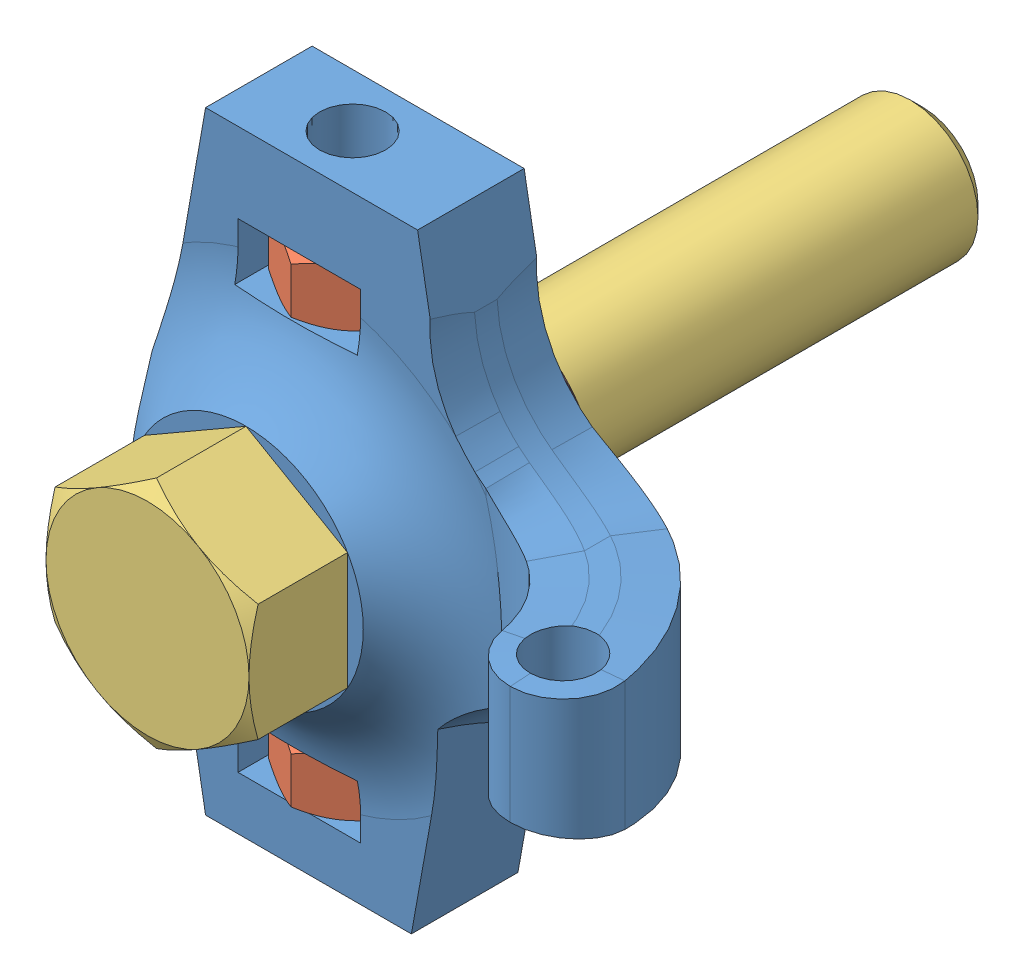
SolidWorks assembly newknuckle right, configuration Default. Lengths in mm.
Overall size (51.11 57.5 72.75).
5 component instances, 4 part files, 8 mates.
Components (placement in the parent):
- ANOTHERKNUCKLEHAHA-1: ANOTHERKNUCKLEHAHA [Default] at (-92.8759 12.7654 19.943) size (51.11 57.5 22.5)
- hex nut style 1_am-1: hex nut style 1_am [B18.2.4.1M - Hex nut, Style 1,  M6 x 1 --D-N] at (-92.8759 30.0654 24.943) x (1 0 0) z (0 -1 0) size (10 11.55 5.2)
- hex nut style 1_am-2: hex nut style 1_am [B18.2.4.1M - Hex nut, Style 1,  M6 x 1 --D-N] at (-92.8759 -9.7346 24.943) x (1 0 0) z (0 -1 0) size (10 11.55 5.2)
- hex bolt_ai-1: hex bolt_ai [HBOLT 0.5000-13x2.5x1.25-N] at (-92.8759 12.7654 44.1886) x (0 0 -1) z (1 0 0) size (72.75 22 19.05)
- hex jam nut_ai-1: hex jam nut_ai [HJNUT 0.5000-13-D-N] at (-92.8759 12.7654 11.7388) x (0.923728 0.383049 0) z (0 0 -1) size (19.05 22 8.2)
Mates (geometry in assembly coordinates):
- Concentric1: concentric anti-aligned: cylinder of ANOTHERKNUCKLEHAHA-1 through (-92.8759 -14.7346 24.943) axis (0 1 0) radius 3.1; cylinder of hex nut style 1_am-1 through (-92.8759 55.1029 24.943) axis (0 -1 0) radius 3
- Coincident1: coincident anti-aligned: plane of ANOTHERKNUCKLEHAHA-1 through (-92.8759 35.2654 29.943) normal (0 -1 0); plane of hex nut style 1_am-1 through (-102.8759 35.2654 24.943) normal (0 1 0)
- Concentric2: concentric anti-aligned: cylinder of ANOTHERKNUCKLEHAHA-1 through (-92.8759 -14.7346 24.943) axis (0 1 0) radius 3.1; cylinder of hex nut style 1_am-2 through (-92.8759 15.3029 24.943) axis (0 -1 0) radius 3
- Coincident2: coincident anti-aligned: plane of ANOTHERKNUCKLEHAHA-1 through (-92.8759 -4.5346 29.943) normal (0 -1 0); plane of hex nut style 1_am-2 through (-102.8759 -4.5346 24.943) normal (0 1 0)
- Concentric3: concentric anti-aligned: cylinder of ANOTHERKNUCKLEHAHA-1 through (-92.8759 12.7654 29.943) axis (0 0 -1) radius 6.4; cylinder of hex bolt_ai-1 through (-92.8759 12.7654 44.1886) axis (0 0 1) radius 6.35
- Coincident3: coincident anti-aligned: plane of ANOTHERKNUCKLEHAHA-1 through (-92.8759 12.7654 34.943) normal (0 0 1); plane of hex bolt_ai-1 through (-92.8759 23.7639 34.943) normal (0 0 -1)
- Concentric4: concentric anti-aligned: cylinder of hex bolt_ai-1 through (-92.8759 12.7654 44.1886) axis (0 0 1) radius 6.35; cylinder of hex jam nut_ai-1 through (-92.8759 12.7654 36.7763) axis (0 0 -1) radius 6.35
- Coincident4: coincident anti-aligned: plane of ANOTHERKNUCKLEHAHA-1 through (-92.8759 12.7654 19.943) normal (0 0 -1); plane of hex jam nut_ai-1 through (-88.663 2.6057 19.943) normal (0 0 1)
